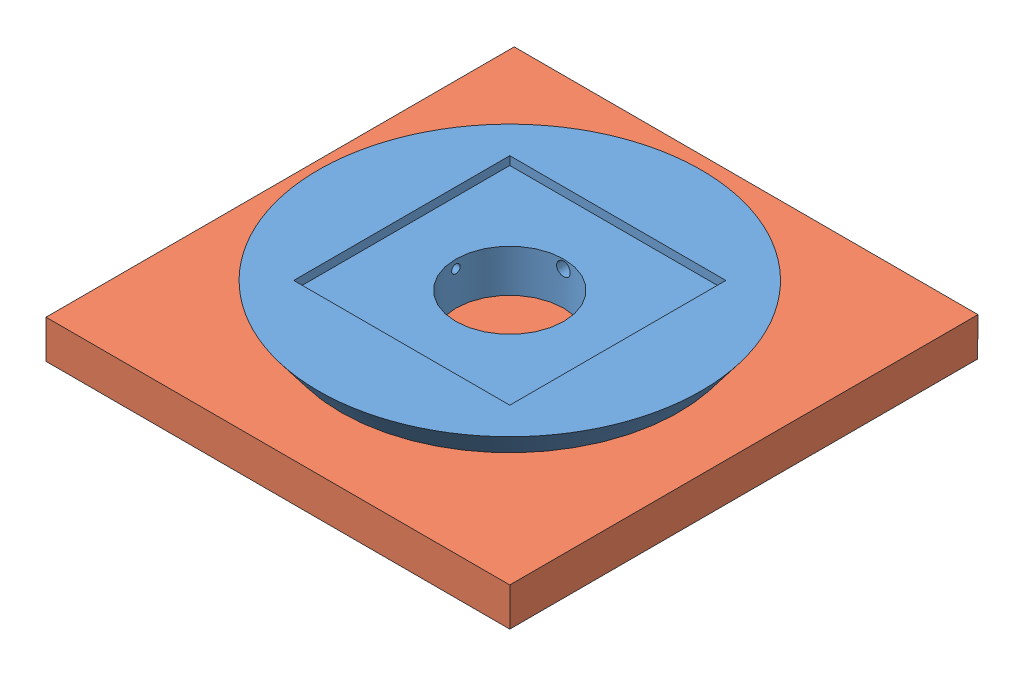
SolidWorks assembly ASI3, configuration Default. Lengths in mm.
Overall size (55 8 55.04).
2 component instances, 2 part files, 12 mates.
Components (placement in the parent):
- innerCircleIteration2-1: innerCircleIteration2 [Default] at (0.1253 -1.4848 0.5275) size (45 6 45)
- Part7-1: Part7 [Default] at (0.1253 -1.4848 0.5275) x (-1 0 0) z (0 -1 0) size (55 55.04 4.5)
Mates (geometry in assembly coordinates):
- InPlace1: in place: plane of assembly through (0 0 0) normal (0 -1 0); plane of ? through (0 0 0) normal (0 -1 0); moOrthogonalPlaneRef_w of assembly through (0 0 0) normal (0 -1 0); unknown of ?; plane of assembly through (0 0 0) normal (0 -1 0); line of ? through (55 -55 0) axis (0 0 -1); plane of assembly through (0 0 0) normal (0 -1 0); unknown of ?
- Coincident1: coincident aligned: plane of innerCircleIteration2-1; plane of ?
- Coincident2: coincident aligned: moOrthogonalPlaneRef_w of innerCircleIteration2-1 through (0 0 0) normal (0 0 -1); plane of ?
- Coincident3: coincident anti-aligned: moOrthogonalPlaneRef_w of innerCircleIteration2-1 through (0 0 0) normal (1 0 0); plane of ?
- InPlace2: in place: plane of assembly through (0 6 0) normal (0 1 0); plane of ? through (0 6 0) normal (0 1 0); plane of assembly through (0 6 0) normal (0 1 0); plane of ? through (0 6 0) normal (0 0 -1); plane of assembly through (0 6 0) normal (0 1 0); line of ? through (-55 0 6) axis (0 1 0); plane of assembly through (0 6 0) normal (0 1 0); unknown of ?
- Coincident4: coincident aligned: plane of innerCircleIteration2-1; plane of ?
- Coincident5: coincident aligned: moOrthogonalPlaneRef_w of innerCircleIteration2-1 through (0 6 0) normal (0 0 -1); plane of ? through (0 6 0) normal (0 0 -1)
- Coincident6: coincident anti-aligned: moOrthogonalPlaneRef_w of innerCircleIteration2-1 through (0 6 0) normal (-1 0 0); plane of ?
- InPlace3: in place: plane of assembly through (0 0 0) normal (0 -1 0); plane of ? through (0 0 0) normal (0 -1 0); plane of assembly through (0 0 0) normal (0 -1 0); unknown of ?; plane of assembly through (0 0 0) normal (0 -1 0); line of ? through (55 -55 0) axis (0 0 -1); plane of innerCircleIteration2-1 through (0.1253 -1.4848 0.5275) normal (0 -1 0); unknown of Part7-1
- Coincident7: coincident aligned: plane of innerCircleIteration2-1; plane of Part7-1
- Coincident8: coincident aligned: moOrthogonalPlaneRef_w of innerCircleIteration2-1 through (0.1253 -1.4848 0.5275) normal (0 0 -1); plane of Part7-1
- Coincident9: coincident anti-aligned: moOrthogonalPlaneRef_w of innerCircleIteration2-1 through (0.1253 -1.4848 0.5275) normal (1 0 0); plane of Part7-1
